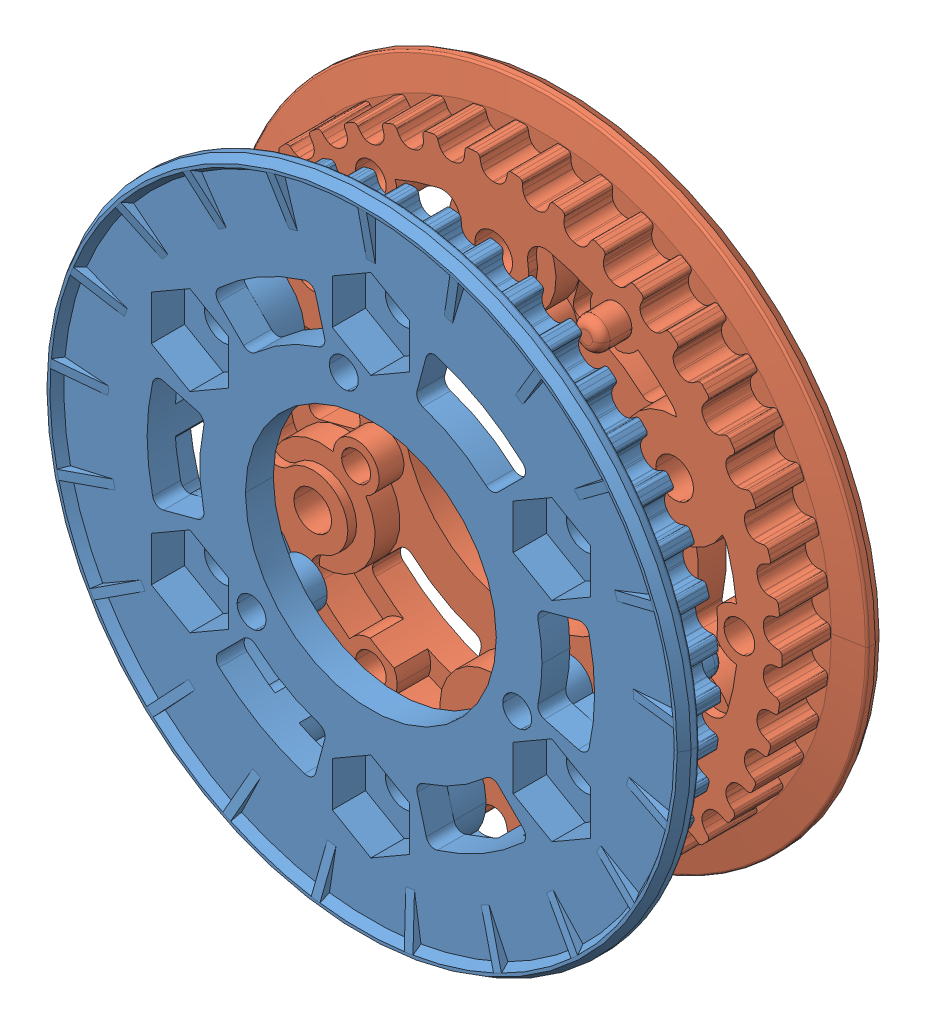
SolidWorks assembly 42t_x_18mm_Wide_VersaPulley_Kit_HTD_5mm_VersaKeys_217-3199, configuration Default. Lengths in mm.
Overall size (73 73 23).
3 component instances, 2 part files, 0 mates.
Components (placement in the parent):
- 42t_x_18mm_Wide_VersaPulley_Kit_HTD_5mm_VersaKeys_217-3199(2)-1: 42t_x_18mm_Wide_VersaPulley_Kit_HTD_5mm_VersaKeys_217-3199(2) [Default] at origin size (73 73 23)
  - 42tVersaPulleyOuter-1: 42tVersaPulleyOuter [Default] at origin size (73 73 11.5)
  - 217-3199-001 Rev4-2: 217-3199-001 Rev4 [Default] at (0 0 -17.825) x (-1 0 0) z (0 0 -1) size (73 73 11.5)
